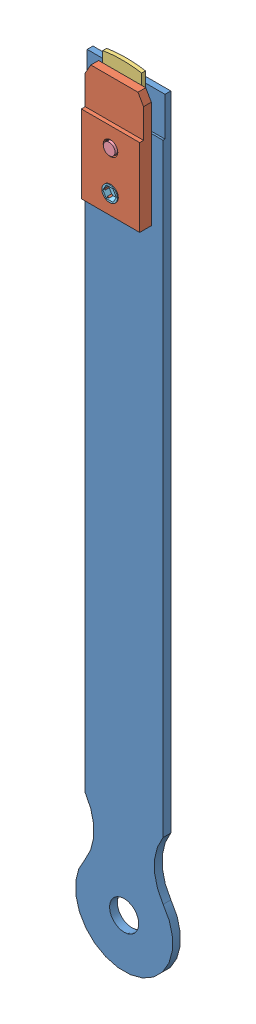
SolidWorks assembly ШаберСб5, configuration По умолчанию. Lengths in mm.
Overall size (50 554.75 12).
5 component instances, 5 part files, 7 mates.
Components (placement in the parent):
- Ручка-1: Ручка [По умолчанию] at origin size (50 554.75 4)
- Прижим-1: Прижим [По умолчанию] at (0 370 5) size (30 60 6)
- Пластина-1: Пластина [По умолчанию] at (-10 380.4431 3) x (1 0 0) z (0 -1 0) size (20 2 27.07)
- ВинтМ6_12-2: ВинтМ6_12 [По умолчанию] at (0 370 11.65) x (0.99876 0.049789 0) z (-0.049789 0.99876 0) size (12 12 12)
- СтопорМ8_8-1: СтопорМ8_8 [По умолчанию] at (0 350 3.45) x (1 0 0) z (0 -1 0) size (8 8 8)
Mates (geometry in assembly coordinates):
- Совпадение4: coincident anti-aligned: plane of Ручка-1 through (25 400 3) normal (0 0 1); plane of Пластина-1 through (2.09 439.2124 3) normal (0 0 -1)
- Расстояние1: distance = 10 mm aligned: plane of Пластина-1 through (10 405.4431 5) normal (1 0 0); plane of Ручка-1 through (20 69.629 4) normal (1 0 0)
- Совпадение7: coincident anti-aligned: plane of Прижим-1 through (0 370 5) normal (0 0 -1); plane of Пластина-1 through (2.09 439.2124 5) normal (0 0 1)
- Совпадение9: coincident aligned: cone of Ручка-1 through (0 370 0) axis (0 0 1); cone of ВинтМ6_12-2 through (0 370 3.25) axis (0 0 1)
- Концентричный1: concentric aligned: cylinder of Ручка-1 through (0 350 4) axis (0 0 -1) radius 3.25; cylinder of Прижим-1 through (0 350 11) axis (0 0 -1) radius 3.25
- Концентричный2: concentric aligned: cylinder of Ручка-1 through (0 370 4) axis (0 0 -1) radius 3.25; cylinder of Прижим-1 through (0 370 11) axis (0 0 -1) radius 3.25
- Совпадение10: coincident aligned: cone of Ручка-1 through (0 350 3.5) axis (0 0 -1); cone of СтопорМ8_8-1 through (0 350 3.45) axis (0 0 -1)
